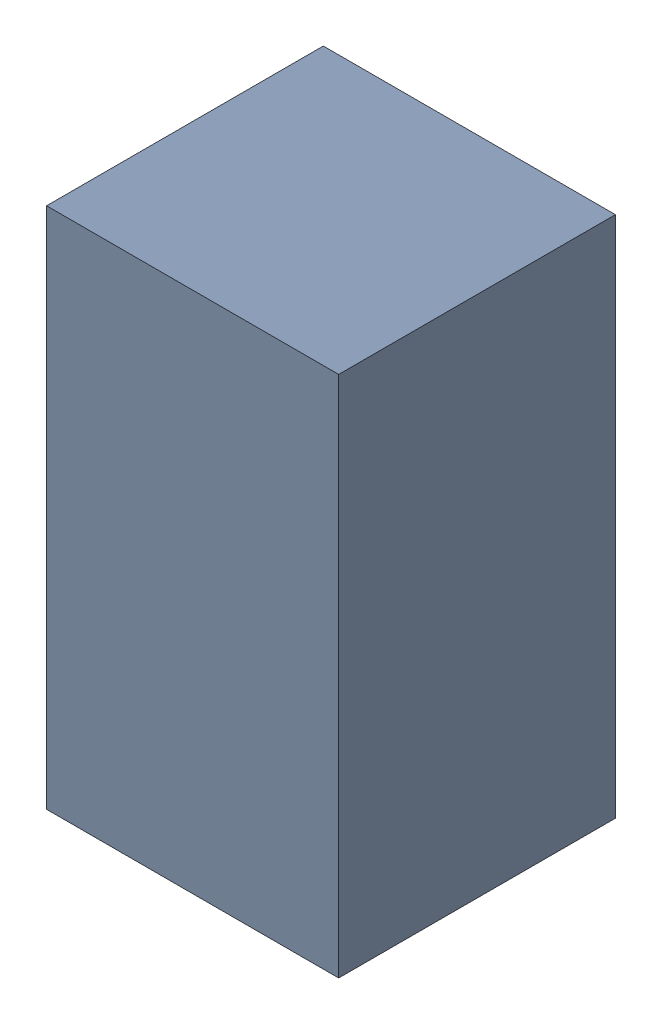
SolidWorks assembly R12, configuration Standard. Lengths in mm.
Overall size (0.95 1.7 0.9).
2 component instances, 1 part files, 0 mates.
Components (placement in the parent):
- 885541560-1: 885541560 [Standard] at (-19 1 0) size (0.95 1.7 0.9)
  - Extruded_16-1: Extruded_16 [Standard] at origin size (0.95 1.7 0.9)
